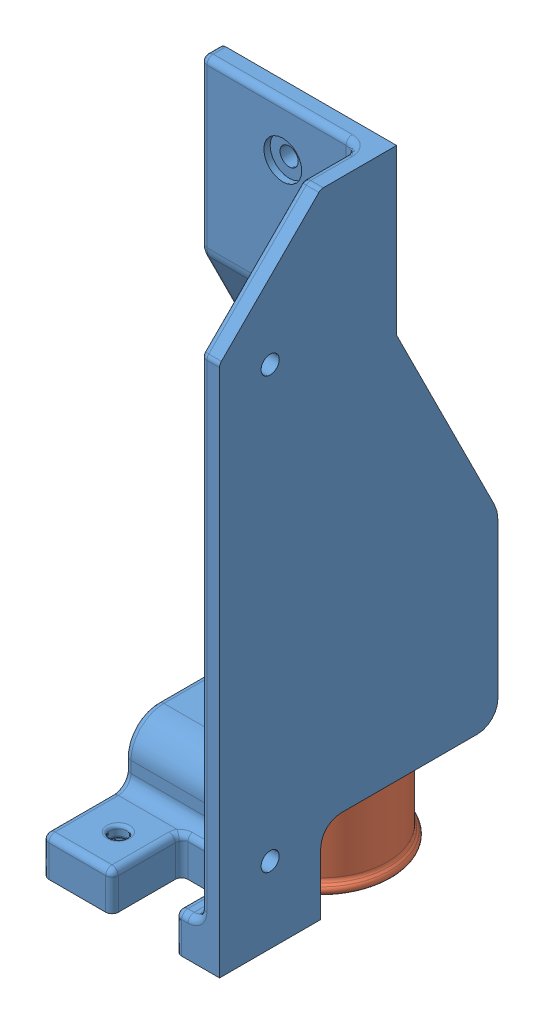
SolidWorks assembly EMERG JETT Brkt Asmbly, configuration Default. Lengths in mm.
Overall size (44.45 163.56 69.85).
9 component instances, 7 part files, 17 mates.
Components (placement in the parent):
- EMERG JETT Brkt-1: EMERG JETT Brkt [Default] at origin size (44.45 158.75 69.85)
- 8-32 18-8 Stainless Steel Hex Nut-1: 8-32 18-8 Stainless Steel Hex Nut [Default] at (-304.8 -128.6256 15.875) x (0 0 -1) z (1 0 0) (suppressed, hidden)
- EMERG JETT Housing-1: EMERG JETT Housing [Default] at (-292.1 -112.7125 -22.225) x (-1 0 0) z (0 0 1) size (36.78 25.45 36.78)
- EMERG JETT Button-1: EMERG JETT Button [Default] at (-292.1 -123.5075 -22.225) x (-1 0 0) z (0 -1 0) size (28.93 28.99 20.32)
- KM1101RR02QE_PART1-1: KM1101RR02QE_PART1 [Default] at (-292.1 -98.4885 -22.225) x (-1 0 0) z (0 0 1) size (9.86 29.64 9.86)
- 1692K520 - SPRING, CONICAL COMPRESSION, .375 OAL X .600 X .313, .262lbs MAX LOAD-1: 1692K520 - SPRING, CONICAL COMPRESSION, .375 OAL X .600 X .313, .262lbs MAX LOAD [1692K52] at (-292.1 -113.9825 -22.225) x (-0.837169 0 -0.546944) z (-0.546944 0 0.837169) size (14.68 9.53 14.49)
- 98430A116 - RING, RETAINING, EXTERNAL, SELF-LOCKING, .125 OD-1: 98430A116 - RING, RETAINING, EXTERNAL, SELF-LOCKING, .125 OD [98430A116] at (-292.1 -107.95 -10.795) x (0 1 0) z (0 0 1) size (0.74 9.3 9.3)
- 98430A116 - RING, RETAINING, EXTERNAL, SELF-LOCKING, .125 OD-2: 98430A116 - RING, RETAINING, EXTERNAL, SELF-LOCKING, .125 OD [98430A116] at (-282.2013 -107.95 -27.94) x (0 1 0) z (0.188455 0 0.982082) size (0.74 9.3 9.3)
- 98430A116 - RING, RETAINING, EXTERNAL, SELF-LOCKING, .125 OD-3: 98430A116 - RING, RETAINING, EXTERNAL, SELF-LOCKING, .125 OD [98430A116] at (-301.9987 -107.95 -27.94) x (0 1 0) z (0.395734 0 0.918365) size (0.74 9.3 9.3)
Mates (geometry in assembly coordinates):
- ProfileCenter2: profile center: plane of EMERG JETT Housing-1 through (-292.1 -112.7125 -26.9875) normal (0 1 0); plane of EMERG JETT Brkt-1 through (-269.875 -112.7125 -44.45) normal (0 -1 0)
- Parallel2: parallel: plane of EMERG JETT Brkt-1 through (-269.875 -53.975 -9.525) normal (1 0 0); plane of EMERG JETT Housing-1 through (-292.1 -112.7125 -22.225) normal (-1 0 0)
- Concentric2: concentric: cylinder of EMERG JETT Housing-1 through (-292.1 -138.1125 -22.225) axis (0 -1 0) radius 15.2273; cylinder of KM1101RR02QE_PART1-1 through (-292.1 -98.4885 -22.225) axis (0 1 0) radius 4.9276
- Coincident7: coincident: plane of EMERG JETT Brkt-1 through (-314.325 -109.5375 4.7625) normal (0 1 0); plane of KM1101RR02QE_PART1-1 through (-292.1 -109.5375 -22.225) normal (0 -1 0)
- InPlace2: in place: plane of KM1101RR02QE_PART1-1 through (-292.1 -123.5075 -22.225) normal (0 -1 0); plane of ? through (0 -123.5075 0) normal (0 -1 0); moOrthogonalPlaneRef_w of KM1101RR02QE_PART1-1 through (-292.1 -123.5075 -22.225) normal (0 -1 0); unknown of ?; plane of KM1101RR02QE_PART1-1 through (-292.1 -123.5075 -22.225) normal (0 -1 0); unknown of ?; plane of KM1101RR02QE_PART1-1 through (-292.1 -123.5075 -22.225) normal (0 -1 0); unknown of EMERG JETT Button-1
- Coincident8: coincident: plane of KM1101RR02QE_PART1-1; plane of EMERG JETT Button-1
- Coincident9: coincident: moOrthogonalPlaneRef_w of KM1101RR02QE_PART1-1 through (-292.1 -123.5075 -22.225) normal (0 0 -1); plane of EMERG JETT Button-1 through (-292.1 -123.5075 -22.225) normal (0 0 -1)
- Coincident10: coincident: moOrthogonalPlaneRef_w of KM1101RR02QE_PART1-1 through (-292.1 -123.5075 -22.225) normal (1 0 0); plane of EMERG JETT Button-1 through (-292.1 -123.5075 -22.225) normal (-1 0 0)
- Concentric3: concentric: cylinder of EMERG JETT Housing-1 through (-292.1 -138.1125 -22.225) axis (0 -1 0) radius 15.2273; line of 1692K520 - SPRING, CONICAL COMPRESSION, .375 OAL X .600 X .313, .262lbs MAX LOAD-1 through (-292.1 -123.9855 -22.225) axis (0 1 0)
- Coincident11: coincident: plane of EMERG JETT Button-1 through (-292.1 -123.5075 -22.225) normal (0 1 0); plane of 1692K520 - SPRING, CONICAL COMPRESSION, .375 OAL X .600 X .313, .262lbs MAX LOAD-1 through (-292.1 -123.5075 -22.225) normal (0 -1 0)
- Parallel3: parallel: plane of EMERG JETT Housing-1 through (-292.1 -112.7125 -22.225) normal (-1 0 0); plane of KM1101RR02QE_PART1-1 through (-292.1 -98.4885 -22.225) normal (-1 0 0)
- Concentric4: concentric: cylinder of EMERG JETT Button-1 through (-292.1 -107.95 -10.795) axis (0 1 0) radius 1.5875; cone of 98430A116 - RING, RETAINING, EXTERNAL, SELF-LOCKING, .125 OD-1 through (-292.1 -107.2134 -10.795) axis (0 1 0)
- Coincident12: coincident: plane of EMERG JETT Button-1 through (-292.1 -107.95 -10.795) normal (0 1 0); circle of 98430A116 - RING, RETAINING, EXTERNAL, SELF-LOCKING, .125 OD-1
- Concentric5: concentric: cylinder of EMERG JETT Button-1 through (-282.2013 -107.95 -27.94) axis (0 1 0) radius 1.5875; cone of 98430A116 - RING, RETAINING, EXTERNAL, SELF-LOCKING, .125 OD-2 through (-282.2013 -107.2134 -27.94) axis (0 1 0)
- Coincident13: coincident: plane of EMERG JETT Button-1 through (-282.2013 -107.95 -27.94) normal (0 1 0); circle of 98430A116 - RING, RETAINING, EXTERNAL, SELF-LOCKING, .125 OD-2
- Concentric6: concentric: cylinder of EMERG JETT Button-1 through (-301.9987 -107.95 -27.94) axis (0 1 0) radius 1.5875; cone of 98430A116 - RING, RETAINING, EXTERNAL, SELF-LOCKING, .125 OD-3 through (-301.9987 -107.2134 -27.94) axis (0 1 0)
- Coincident14: coincident: plane of EMERG JETT Button-1 through (-301.9987 -107.95 -27.94) normal (0 1 0); circle of 98430A116 - RING, RETAINING, EXTERNAL, SELF-LOCKING, .125 OD-3
